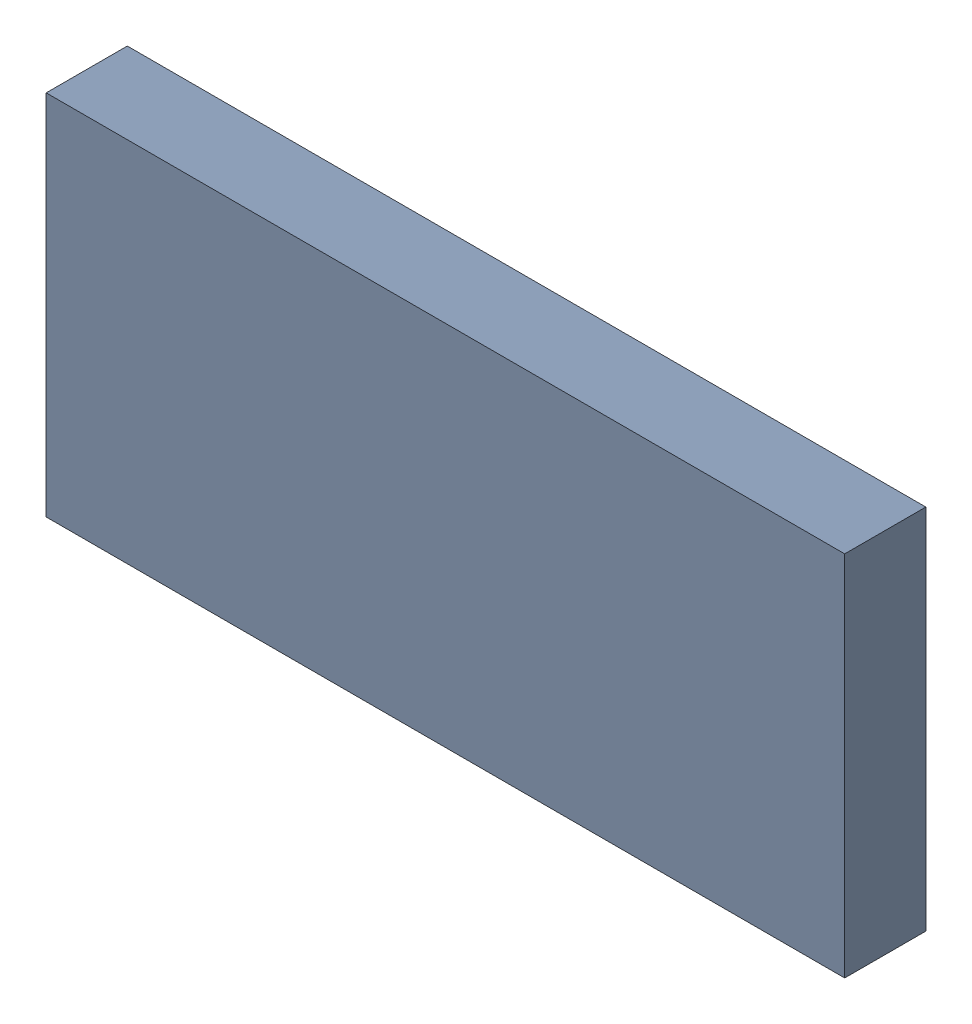
SolidWorks assembly 6327399808, configuration Default. Lengths in mm.
Overall size (2.5 1.15 0.25).
2 component instances, 1 part files, 0 mates.
Components (placement in the parent):
- 6701982208-1:  [Default] at (27.7 14.8 0) (suppressed, hidden)
- Extruded-11-1: Extruded-11 [Default] at origin size (2.5 1.15 0.25)
